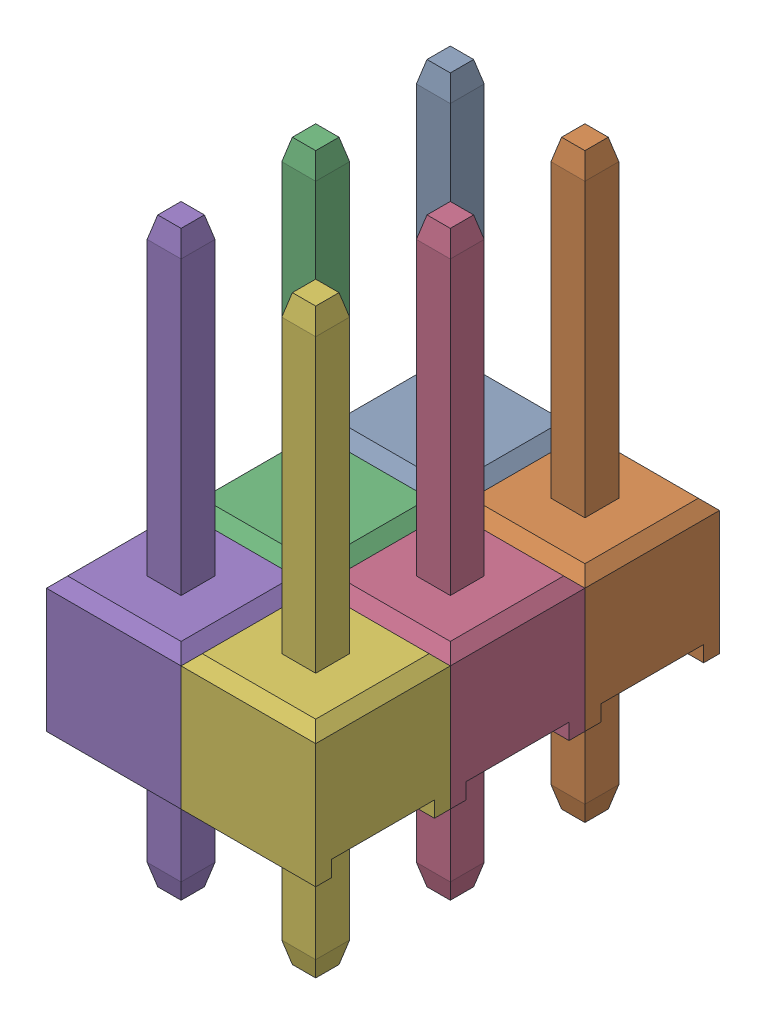
SolidWorks assembly User Library-BluePill_User_Library-Header3x2_100_TH, configuration Default. Lengths in mm.
Overall size (5.08 10.98 7.62).
9 component instances, 1 part files, 0 mates.
Components (placement in the parent):
- User Library-BluePill_User_Library-Header3x2_100_TH_User_Library-Header1x2-1: User Library-BluePill_User_Library-Header3x2_100_TH_User_Library-Header1x2 [Default] at (-5.6755 -6.84 9.2218) size (5.08 10.98 2.54)
  - User Library-BluePill_User_Library-Header3x2_100_TH_User_Library-Header1x2_Header1_1-1: User Library-BluePill_User_Library-Header3x2_100_TH_User_Library-Header1x2_Header1_1 [Default] at (4.4052 8.1155 -11.7669) size (2.54 10.98 2.54)
  - User Library-BluePill_User_Library-Header3x2_100_TH_User_Library-Header1x2_Header1_1-2: User Library-BluePill_User_Library-Header3x2_100_TH_User_Library-Header1x2_Header1_1 [Default] at (6.9452 8.1155 -11.7669) size (2.54 10.98 2.54)
- User Library-BluePill_User_Library-Header3x2_100_TH_User_Library-Header1x2-2: User Library-BluePill_User_Library-Header3x2_100_TH_User_Library-Header1x2 [Default] at (-5.6755 -6.84 11.7618) size (5.08 10.98 2.54)
  - User Library-BluePill_User_Library-Header3x2_100_TH_User_Library-Header1x2_Header1_1-1: User Library-BluePill_User_Library-Header3x2_100_TH_User_Library-Header1x2_Header1_1 [Default] at (4.4052 8.1155 -11.7669) size (2.54 10.98 2.54)
  - User Library-BluePill_User_Library-Header3x2_100_TH_User_Library-Header1x2_Header1_1-2: User Library-BluePill_User_Library-Header3x2_100_TH_User_Library-Header1x2_Header1_1 [Default] at (6.9452 8.1155 -11.7669) size (2.54 10.98 2.54)
- User Library-BluePill_User_Library-Header3x2_100_TH_User_Library-Header1x2-3: User Library-BluePill_User_Library-Header3x2_100_TH_User_Library-Header1x2 [Default] at (-5.6755 -6.84 14.3018) size (5.08 10.98 2.54)
  - User Library-BluePill_User_Library-Header3x2_100_TH_User_Library-Header1x2_Header1_1-1: User Library-BluePill_User_Library-Header3x2_100_TH_User_Library-Header1x2_Header1_1 [Default] at (4.4052 8.1155 -11.7669) size (2.54 10.98 2.54)
  - User Library-BluePill_User_Library-Header3x2_100_TH_User_Library-Header1x2_Header1_1-2: User Library-BluePill_User_Library-Header3x2_100_TH_User_Library-Header1x2_Header1_1 [Default] at (6.9452 8.1155 -11.7669) size (2.54 10.98 2.54)
